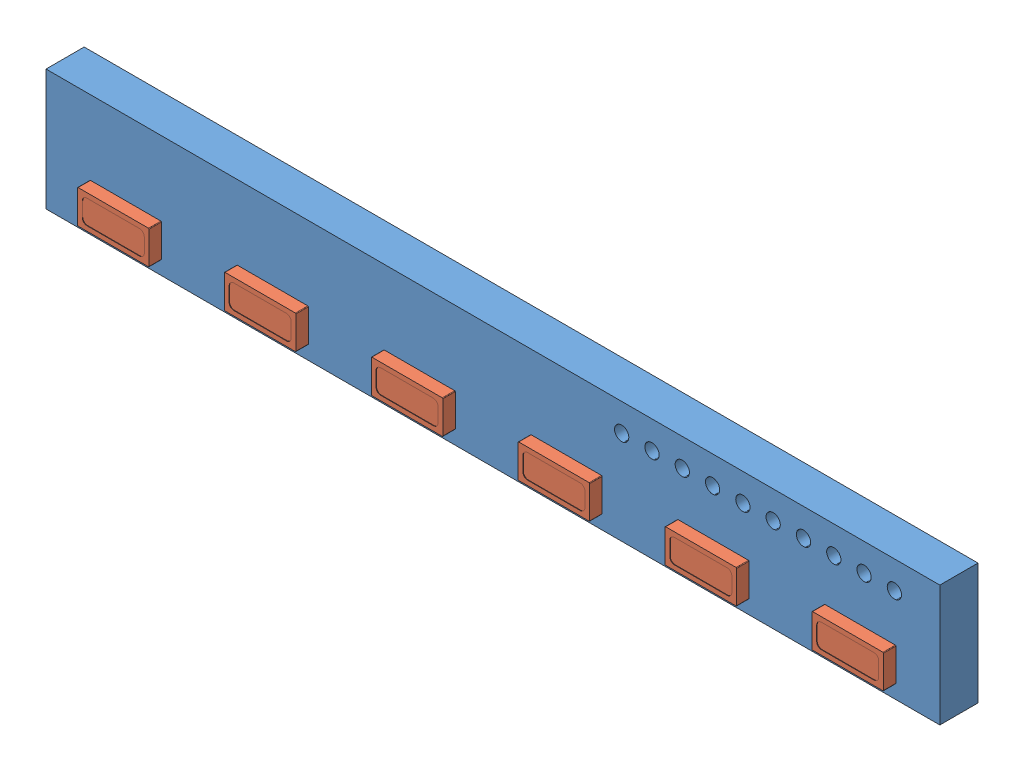
SolidWorks assembly PCB_SIDE_LED_L, configuration Default. Lengths in mm.
Overall size (37.46 5.08 2.12).
7 component instances, 2 part files, 3 mates.
Components (placement in the parent):
- LEDPanel2L-1: LEDPanel2L [Default] at (-12.1342 0.9368 4.9666) size (37.46 5.08 1.6)
- 1206_5000k_LUMINUS_MP3014_1100-1: 1206_5000k_LUMINUS_MP3014_1100 [Default] at (-27.5267 -0.3332 6.5666) x (0 1 0) z (1 0 0) size (1.4 0.52 3)
- 1206_5000k_LUMINUS_MP3014_1100-2: 1206_5000k_LUMINUS_MP3014_1100 [Default] at (-21.3698 -0.3332 6.5666) x (0 1 0) z (1 0 0) size (1.4 0.52 3)
- 1206_5000k_LUMINUS_MP3014_1100-3: 1206_5000k_LUMINUS_MP3014_1100 [Default] at (-15.2128 -0.3332 6.5666) x (0 1 0) z (1 0 0) size (1.4 0.52 3)
- 1206_5000k_LUMINUS_MP3014_1100-4: 1206_5000k_LUMINUS_MP3014_1100 [Default] at (-9.0558 -0.3332 6.5666) x (0 1 0) z (1 0 0) size (1.4 0.52 3)
- 1206_5000k_LUMINUS_MP3014_1100-5: 1206_5000k_LUMINUS_MP3014_1100 [Default] at (-2.8989 -0.3332 6.5666) x (0 1 0) z (1 0 0) size (1.4 0.52 3)
- 1206_5000k_LUMINUS_MP3014_1100-9: 1206_5000k_LUMINUS_MP3014_1100 [Default] at (3.2581 -0.3332 6.5666) x (0 1 0) z (1 0 0) size (1.4 0.52 3)
Mates (geometry in assembly coordinates):
- Coincident1: coincident: plane of LEDPanel2L-1 through (-12.1342 0.9368 6.5666) normal (0 0 1); plane of 1206_5000k_LUMINUS_MP3014_1100-1 through (-29.0017 -1.0082 6.5666) normal (0 0 -1)
- Distance1: distance = 1.27 mm: plane of 1206_5000k_LUMINUS_MP3014_1100-1 through (-27.5267 -0.3332 6.5666) normal (0 1 0); plane of LEDPanel2L-1 through (-30.8667 -1.6032 6.5666) normal (0 -1 0)
- Coincident3: coincident: point of LEDPanel2L-1; plane of 1206_5000k_LUMINUS_MP3014_1100-1 through (-27.5267 -0.3332 6.5666) normal (1 0 0)
